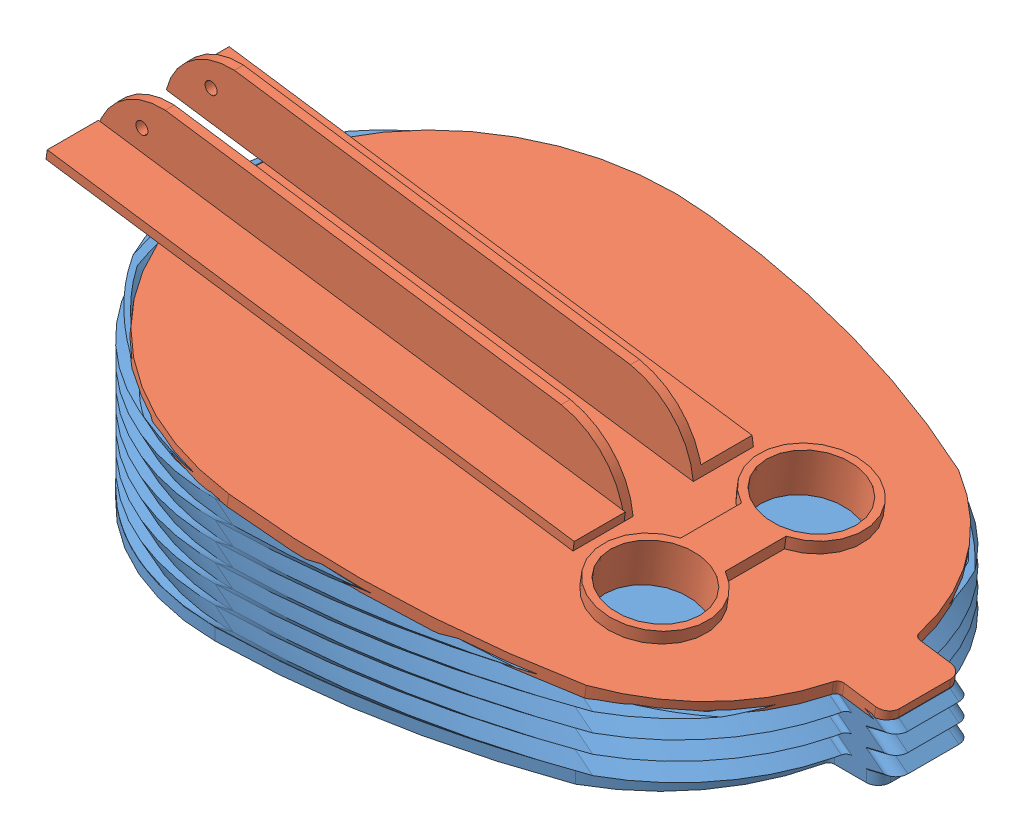
SolidWorks assembly fuelle final, configuration Default. Lengths in mm.
Overall size (268.55 81.15 167.56).
2 component instances, 2 part files, 2 mates.
Components (placement in the parent):
- tapa de fuelle2-1: tapa de fuelle2 [Default] at (-152.7076 -104.847 127.3442) size (241.61 60.29 167.56)
- tapa sup de fuelle-1: tapa sup de fuelle [Default] at (-148.9439 -68.1365 127.3442) x (0.989823 -0.142307 0) z (0 0 1) size (265 43.89 160.08)
Mates (geometry in assembly coordinates):
- Concentric1: concentric: cylinder of tapa de fuelle2-1 through (-61.6802 -96.847 182.3442) axis (0 0 -1) radius 2; cylinder of tapa sup de fuelle-1 through (-61.6802 -96.847 93.3442) axis (0 0 1) radius 2
- Coincident1: coincident: plane of tapa de fuelle2-1 through (-64.6802 -92.847 152.3442) normal (0 0 -1); plane of tapa sup de fuelle-1 through (-65.2189 -100.3794 152.3442) normal (0 0 1)
